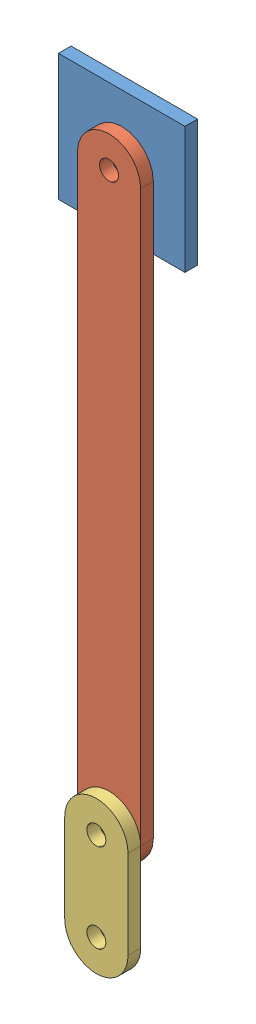
SolidWorks assembly Assemblage manege, configuration Défaut. Lengths in mm.
Overall size (1000 5950 300).
3 component instances, 3 part files, 6 mates.
Components (placement in the parent):
- Chassis 0-1: Chassis 0 [Défaut] at origin size (1000 1000 100)
- Bras 1-1: Bras 1 [Défaut] at (0 -4500 100) x (0 1 0) z (0 0 1) size (5000 500 100)
- Nacelle 2-1: Nacelle 2 [Défaut] at (0 -4500 200) x (0 -1 0) z (0 0 1) size (1200 500 100)
Mates (geometry in assembly coordinates):
- Coaxiale1: concentric: cylinder of Chassis 0-1 through (0 0 100) axis (0 0 -1) radius 75; cylinder of Bras 1-1 through (0 0 200) axis (0 0 -1) radius 75
- Coaxiale2: concentric: cylinder of Bras 1-1 through (0 -4500 200) axis (0 0 -1) radius 75; cylinder of Nacelle 2-1 through (0 -4500 300) axis (0 0 -1) radius 75
- Coïncidente2: coincident: plane of Bras 1-1 through (0 -4500 200) normal (0 0 1); plane of Nacelle 2-1 through (0 -4500 200) normal (0 0 -1)
- Coïncidente3: coincident: plane of Chassis 0-1 through (0 0 100) normal (0 0 1); plane of Bras 1-1 through (0 -4500 100) normal (0 0 -1)
- Parallèle1: parallel aligned: plane of Chassis 0-1 through (500 500 100) normal (1 0 0); plane of Bras 1-1 through (250 -4500 200) normal (1 0 0)
- Parallèle2: parallel aligned: plane of Bras 1-1; plane of Nacelle 2-1 through (250 -4500 300) normal (1 0 0)
